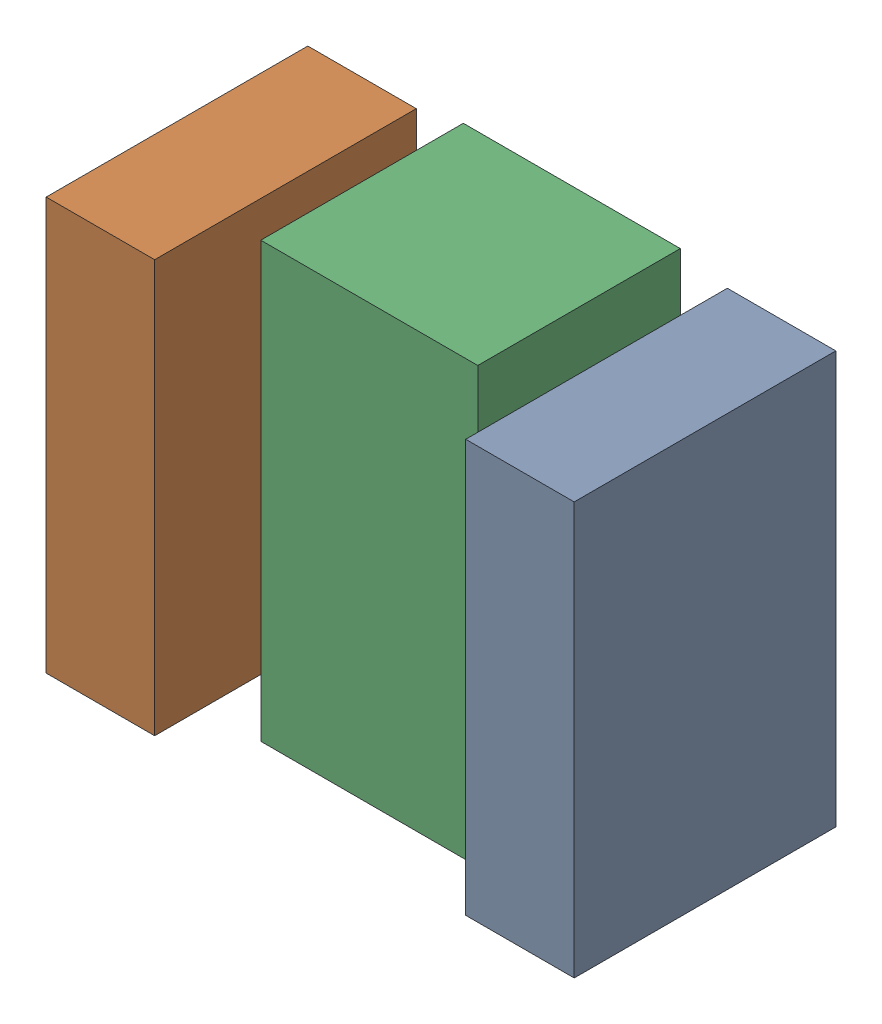
SolidWorks assembly C11_Motor_7Kanaloa_v2.0.0_Motor, configuration Default. Lengths in mm.
Overall size (3.65 3 1.81).
6 component instances, 2 part files, 0 mates.
Components (placement in the parent):
- 334788400-1: 334788400 [Default] at (78.872 135.636 0) size (0.75 2.85 1.81)
  - Extruded_5-1: Extruded_5 [Default] at origin size (0.75 2.85 1.81)
- 334788400-2: 334788400 [Default] at (75.972 135.636 0) size (0.75 2.85 1.81)
  - Extruded_5-1: Extruded_5 [Default] at origin size (0.75 2.85 1.81)
- 334788656-1: 334788656 [Default] at (77.422 135.636 0) size (1.5 3 1.4)
  - Extruded_1-1: Extruded_1 [Default] at origin size (1.5 3 1.4)
